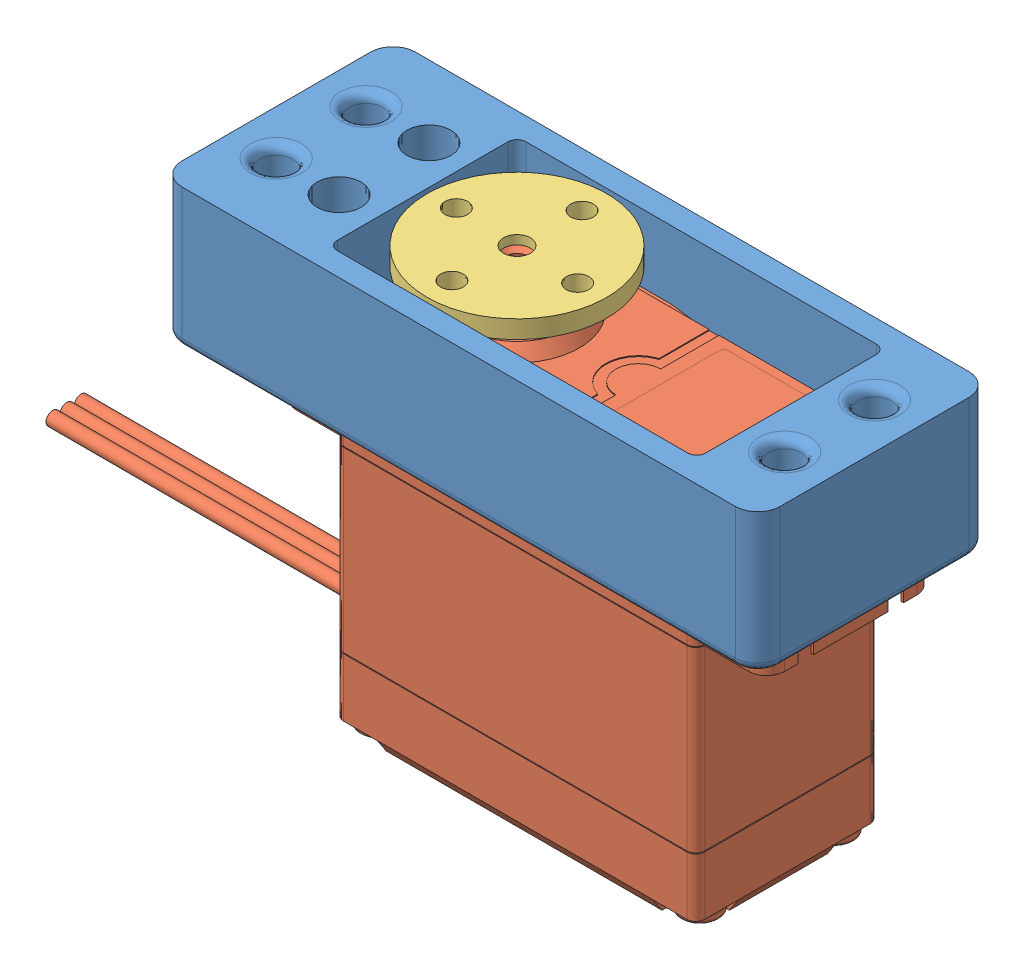
SolidWorks assembly Mounted DS3225 5, configuration Default. Lengths in mm.
Overall size (89.9 46.91 26).
3 component instances, 3 part files, 5 mates.
Components (placement in the parent):
- DS3225_Mount_5-1: DS3225_Mount_5 [Default] at (14.6825 29.7781 44.975) size (66.6 15.6 26)
- SW2020 DS3225MG Servo 25Kg 4.8-6.8V-1: SW2020 DS3225MG Servo 25Kg 4.8-6.8V [Default] at (-5.3175 44.3781 44.975) x (1 0 0) z (0 1 0) size (87.25 20.4 45.91)
- Aluminum Servo horn v2.step-1: Aluminum Servo horn v2.step [Default] at (-5.3175 45.3781 44.975) x (0.999372 0 0.035422) z (0.035422 0 -0.999372) size (20 4.5 20)
Mates (geometry in assembly coordinates):
- Concentric1: concentric aligned: cylinder of DS3225_Mount_5-1 through (-20.1175 45.3781 39.975) axis (0 -1 0) radius 2.45; cylinder of SW2020 DS3225MG Servo 25Kg 4.8-6.8V-1 through (-20.1175 44.3781 39.975) axis (0 -1 0) radius 2.25
- Concentric2: concentric aligned: cylinder of DS3225_Mount_5-1 through (29.4825 45.3781 49.975) axis (0 -1 0) radius 1.85; cylinder of SW2020 DS3225MG Servo 25Kg 4.8-6.8V-1 through (29.4825 44.3781 49.975) axis (0 -1 0) radius 2.25
- Coincident1: coincident anti-aligned: plane of SW2020 DS3225MG Servo 25Kg 4.8-6.8V-1 through (-5.3175 44.3781 44.975) normal (0 1 0); plane of Aluminum Servo horn v2.step-1 through (-5.3175 44.3781 44.975) normal (0 -1 0)
- Concentric3: concentric anti-aligned: cylinder of SW2020 DS3225MG Servo 25Kg 4.8-6.8V-1 through (-5.3175 44.3781 44.975) axis (0 1 0) radius 1.25; cylinder of Aluminum Servo horn v2.step-1 through (-5.3175 45.3781 44.975) axis (0 -1 0) radius 10
- Coincident3: coincident anti-aligned: plane of DS3225_Mount_5-1 through (-29.6175 29.7781 34.475) normal (0 -1 0); plane of SW2020 DS3225MG Servo 25Kg 4.8-6.8V-1 through (-5.3175 29.7781 44.975) normal (0 1 0)
